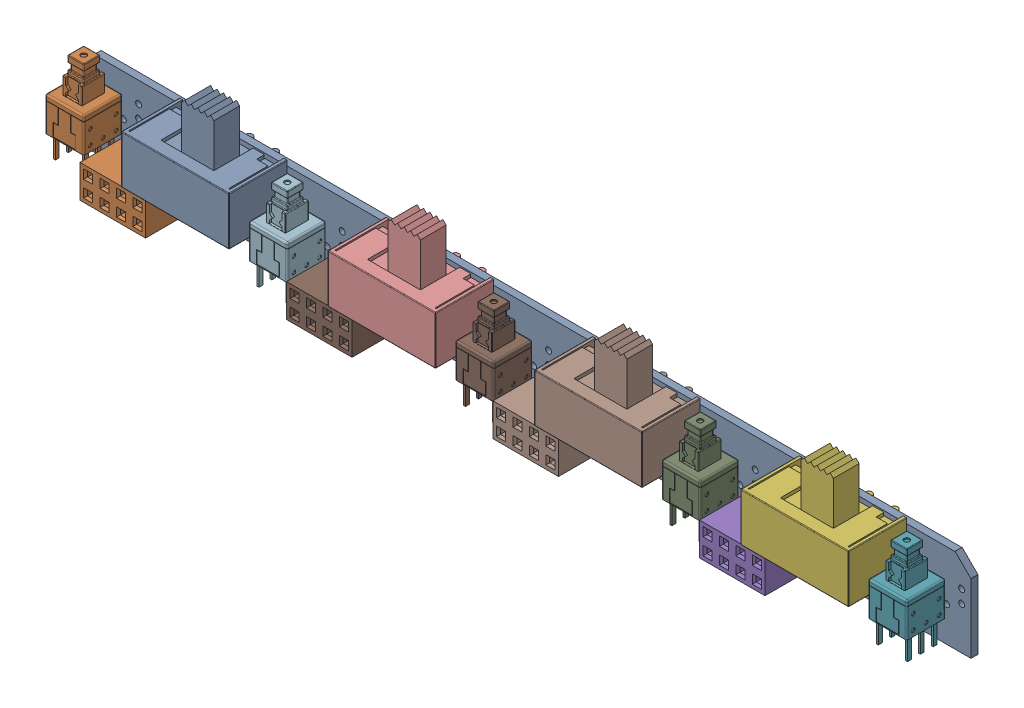
SolidWorks assembly Pedal_SW, configuration Default. Lengths in mm.
Overall size (138.5 20.99 12).
48 component instances, 6 part files, 0 mates.
Components (placement in the parent):
- Board-1: Board [Default] at origin size (138.5 13.14 1.09)
  - Open CASCADE STEP translator 7.5 4.1.1-1: Open CASCADE STEP translator 7.5 4.1.1 [Default] at (0 0 -1.0914) size (138.5 13.14 1.09)
- MH12-1: MH12 [Default] at origin size (1 1 2)
  - 9228463120-1: 9228463120 [Default] at (144.979 80.6107 -1.5) size (1 1 2)
    - Cylinder-1: Cylinder [Default] at origin size (1 1 2)
- MH11-1: MH11 [Default] at origin size (1 1 2)
  - 9228463120-1: 9228463120 [Default] at (112.979 80.6107 -1.5) size (1 1 2)
    - Cylinder-1: Cylinder [Default] at origin size (1 1 2)
- MH10-1: MH10 [Default] at origin size (1 1 2)
  - 9228463120-1: 9228463120 [Default] at (80.979 80.6107 -1.5) size (1 1 2)
    - Cylinder-1: Cylinder [Default] at origin size (1 1 2)
- MH9-1: MH9 [Default] at origin size (1 1 2)
  - 9228463120-1: 9228463120 [Default] at (48.979 80.6107 -1.5) size (1 1 2)
    - Cylinder-1: Cylinder [Default] at origin size (1 1 2)
- SW5-1: SW5 [Default] at origin size (16.7 14.6 12)
  - MFS201N-16-Z-1: MFS201N-16-Z [Default] at (156.468 81.836 0) x (1 0 0) z (0 -1 0) size (16.7 12 14.6)
- SW1-1: SW1 [Default] at origin size (6 14 6)
  - SW-MHPS2266-1: SW-MHPS2266 [Default] at (169.904 77.181 5.048) x (0 0 -1) z (0 1 0) size (6 6 14)
- SW6-1: SW6 [Default] at origin size (16.7 14.6 12)
  - MFS201N-16-Z-1: MFS201N-16-Z [Default] at (124.468 81.836 0) x (1 0 0) z (0 -1 0) size (16.7 12 14.6)
- SW2-1: SW2 [Default] at origin size (6 14 6)
  - SW-MHPS2266-1: SW-MHPS2266 [Default] at (137.904 77.181 5.048) x (0 0 -1) z (0 1 0) size (6 6 14)
- SW7-1: SW7 [Default] at origin size (16.7 14.6 12)
  - MFS201N-16-Z-1: MFS201N-16-Z [Default] at (92.468 81.836 0) x (1 0 0) z (0 -1 0) size (16.7 12 14.6)
- SW3-1: SW3 [Default] at origin size (6 14 6)
  - SW-MHPS2266-1: SW-MHPS2266 [Default] at (105.904 77.181 5.048) x (0 0 -1) z (0 1 0) size (6 6 14)
- SW4-1: SW4 [Default] at origin size (6 14 6)
  - SW-MHPS2266-1: SW-MHPS2266 [Default] at (73.904 77.181 5.048) x (0 0 -1) z (0 1 0) size (6 6 14)
- SW8-1: SW8 [Default] at origin size (16.7 14.6 12)
  - MFS201N-16-Z-1: MFS201N-16-Z [Default] at (60.468 81.836 0) x (1 0 0) z (0 -1 0) size (16.7 12 14.6)
- X4-1: X4 [Default] at origin size (10.16 5.08 11.5)
  - PBD-8-1: PBD-8 [Default] at (50.2961 75.1841 0) x (0 0 1) z (-1 0 0) size (11.5 5.08 10.16)
- X3-1: X3 [Default] at origin size (10.16 5.08 11.5)
  - PBD-8-1: PBD-8 [Default] at (82.2961 75.1841 0) x (0 0 1) z (-1 0 0) size (11.5 5.08 10.16)
- X2-1: X2 [Default] at origin size (10.16 5.08 11.5)
  - PBD-8-1: PBD-8 [Default] at (114.2961 75.1841 0) x (0 0 1) z (-1 0 0) size (11.5 5.08 10.16)
- Open CASCADE STEP translator 7.5 4.17-1: Open CASCADE STEP translator 7.5 4.17 [Default] at origin size (10.16 5.08 11.5)
  - PBD-8-1: PBD-8 [Default] at (146.2961 75.1841 0) x (0 0 1) z (-1 0 0) size (11.5 5.08 10.16)
- SW9-1: SW9 [Default] at origin size (6 14 6)
  - SW-MHPS2266-1: SW-MHPS2266 [Default] at (42.354 78.481 5.048) x (0 0 -1) z (0 1 0) size (6 6 14)
- R4-1: R4 [Default] at origin size (0.8 1.6 0.45)
  - 0603 resistor-1: 0603 resistor [Default] at (61.196 75.0101 0) x (0 -1 0) z (-1 0 0) size (1.6 0.45 0.8)
- R1-1: R1 [Default] at origin size (0.8 1.6 0.45)
  - 0603 resistor-1: 0603 resistor [Default] at (157.208 75.0101 0) x (0 -1 0) z (-1 0 0) size (1.6 0.45 0.8)
- R2-1: R2 [Default] at origin size (0.8 1.6 0.45)
  - 0603 resistor-1: 0603 resistor [Default] at (125.204 75.0101 0) x (0 -1 0) z (-1 0 0) size (1.6 0.45 0.8)
- R3-1: R3 [Default] at origin size (0.8 1.6 0.45)
  - 0603 resistor-1: 0603 resistor [Default] at (93.2 75.0101 0) x (0 -1 0) z (-1 0 0) size (1.6 0.45 0.8)
